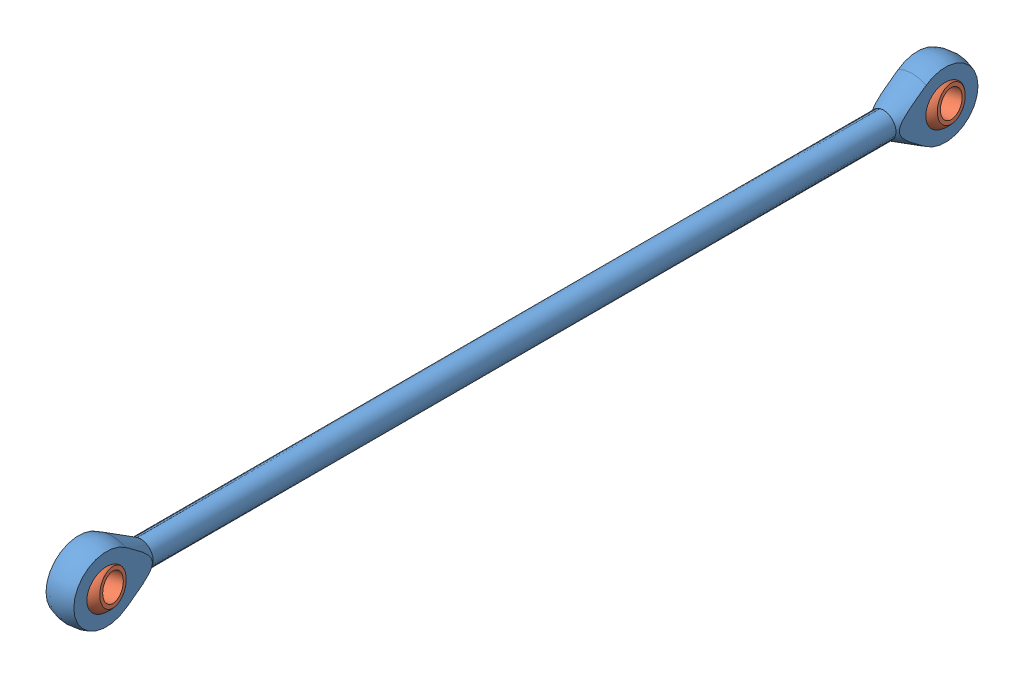
SolidWorks assembly distal-link, configuration Default. Lengths in mm.
Overall size (18.19 28.1 360.19).
4 component instances, 2 part files, 2 mates.
Components (placement in the parent):
- distal-link^distal-link-1: distal-link^distal-link [Default] at origin size (18.19 28.1 360.19) (virtual)
  - distal-link-housing-1: distal-link-housing [Default] at origin size (11 28.1 360.1)
  - distal-link-sphere-1: distal-link-sphere [Default] x (0.136884 -0.928274 0.34579) z (0.093546 0.359629 0.928394) size (19 14 19)
  - distal-link-sphere-2: distal-link-sphere [Default] at (0 0 332) x (0.206065 -0.516188 0.831317) z (0.002654 0.849841 0.527032) size (19 14 19)
Mates (geometry in assembly coordinates):
- Coincident8: coincident: point of distal-link^distal-link-1/distal-link-sphere-1; point of assembly
- LimitAngle12: limit planar angle = 0.166565 rad: plane of assembly through (0 0 0) normal (1 0 0); plane of distal-link^distal-link-1/distal-link-sphere-1 through (0 0 0) normal (0.98616 0.094735 -0.136064)
